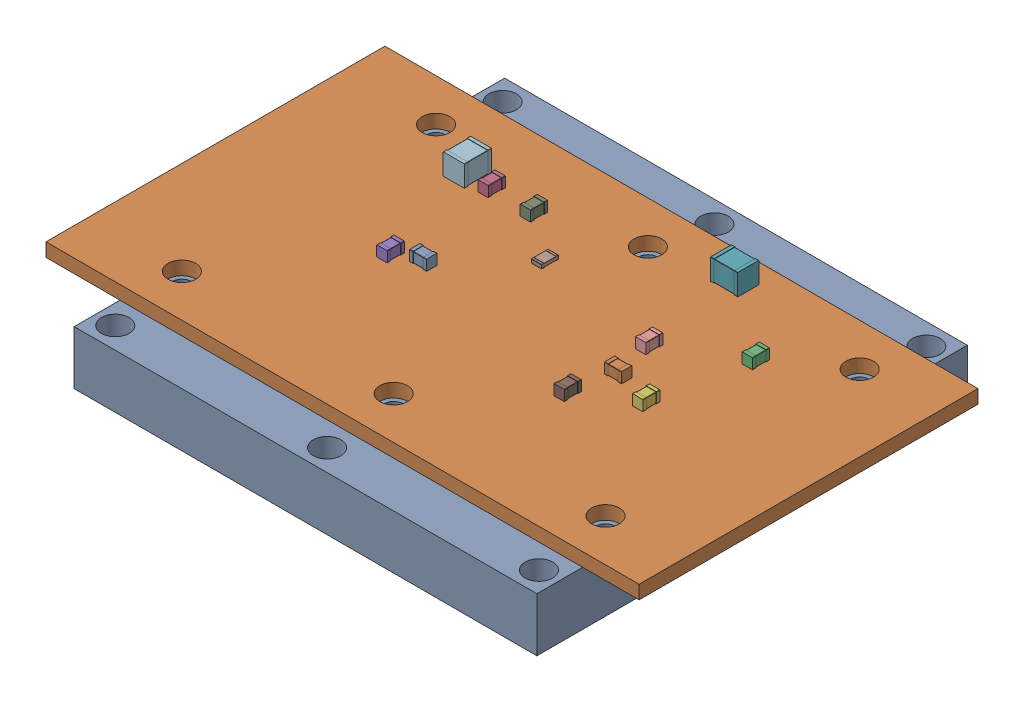
SolidWorks assembly Heatsink_assembly, configuration Default. Lengths in mm.
Overall size (70 10.5 50.8).
28 component instances, 5 part files, 3 mates.
Components (placement in the parent):
- Heat_Spreader-1: Heat_Spreader [Default] at origin size (54.61 6.35 50.8)
- S-Band Amplifier-1: S-Band Amplifier [Default] at (-80 6.35 -90) x (1 0 0) z (0 1 0) size (70 40 4.15)
  - S-Band Amplifier(2)-1: S-Band Amplifier(2) [Default] at origin size (70 40 4.15)
    - C_0805_2012Metric-1: C_0805_2012Metric [Default] at (91.5 -90 1.65) size (2 1.25 1.25)
      - C_0805_2012Metric-0-1: C_0805_2012Metric-0 [Default] at origin size (2 1.25 1.25)
    - C_0805_2012Metric-2: C_0805_2012Metric [Default] at (98.19 -80.45 1.65) x (0 -1 0) z (0 0 1) size (2 1.25 1.25)
      - C_0805_2012Metric-0-1: C_0805_2012Metric-0 [Default] at origin size (2 1.25 1.25)
    - C_0805_2012Metric-3: C_0805_2012Metric [Default] at (65 -78.45 1.65) x (0 1 0) z (0 0 1) size (2 1.25 1.25)
      - C_0805_2012Metric-0-1: C_0805_2012Metric-0 [Default] at origin size (2 1.25 1.25)
    - C_0805_2012Metric-4: C_0805_2012Metric [Default] at (65.7 -91.075 1.65) x (0 -1 0) z (0 0 1) size (2 1.25 1.25)
      - C_0805_2012Metric-0-1: C_0805_2012Metric-0 [Default] at origin size (2 1.25 1.25)
    - C_0805_2012Metric-5: C_0805_2012Metric [Default] at (96 -91.2 1.65) x (0 1 0) z (0 0 1) size (2 1.25 1.25)
      - C_0805_2012Metric-0-1: C_0805_2012Metric-0 [Default] at origin size (2 1.25 1.25)
    - C_1210_3225Metric-1: C_1210_3225Metric [Default] at (88.875 -73.63 1.65) x (-1 0 0) z (0 0 1) size (3.2 2.5 2.5)
      - C_1210_3225Metric-1-1: C_1210_3225Metric-1 [Default] at origin size (3.2 2.5 2.5)
    - R_0805_2012Metric-1: R_0805_2012Metric [Default] at (75.45 -82.6 1.65) x (0 -1 0) z (0 0 1) size (2 1.2 0.45)
      - R_0805_2012Metric-2-1: R_0805_2012Metric-2 [Default] at origin size (2 1.2 0.45)
    - C_0805_2012Metric-6: C_0805_2012Metric [Default] at (70 -78.45 1.65) x (0 1 0) z (0 0 1) size (2 1.25 1.25)
      - C_0805_2012Metric-0-1: C_0805_2012Metric-0 [Default] at origin size (2 1.25 1.25)
    - C_0805_2012Metric-7: C_0805_2012Metric [Default] at (90.35 -85.2 1.65) x (0 1 0) z (0 0 1) size (2 1.25 1.25)
      - C_0805_2012Metric-0-1: C_0805_2012Metric-0 [Default] at origin size (2 1.25 1.25)
    - C_0805_2012Metric-8: C_0805_2012Metric [Default] at (90.325 -94.8 1.65) x (0 -1 0) z (0 0 1) size (2 1.25 1.25)
      - C_0805_2012Metric-0-1: C_0805_2012Metric-0 [Default] at origin size (2 1.25 1.25)
    - C_1210_3225Metric-2: C_1210_3225Metric [Default] at (62 -78.3 1.65) x (0 1 0) z (0 0 1) size (3.2 2.5 2.5)
      - C_1210_3225Metric-1-1: C_1210_3225Metric-1 [Default] at origin size (3.2 2.5 2.5)
    - C_0805_2012Metric-9: C_0805_2012Metric [Default] at (68.5 -90 1.65) size (2 1.25 1.25)
      - C_0805_2012Metric-0-1: C_0805_2012Metric-0 [Default] at origin size (2 1.25 1.25)
    - S-Band Amplifier_PCB-1: S-Band Amplifier_PCB [Default] at origin size (70 40 1.6)
Mates (geometry in assembly coordinates):
- Concentric1: concentric: cylinder of Heat_Spreader-1 through (-25 6.35 -15) axis (0 1 0) radius 1.1303; circle of S-Band Amplifier-1/S-Band Amplifier(2)-1/S-Band Amplifier_PCB-1
- Concentric2: concentric: cylinder of Heat_Spreader-1 through (-25 6.35 15) axis (0 1 0) radius 1.1303; circle of S-Band Amplifier-1/S-Band Amplifier(2)-1/S-Band Amplifier_PCB-1
- Coincident1: coincident anti-aligned: plane of Heat_Spreader-1 through (0 6.35 0) normal (0 1 0); plane of S-Band Amplifier-1/S-Band Amplifier(2)-1/S-Band Amplifier_PCB-1 through (-1.035 6.35 0) normal (0 -1 0)
